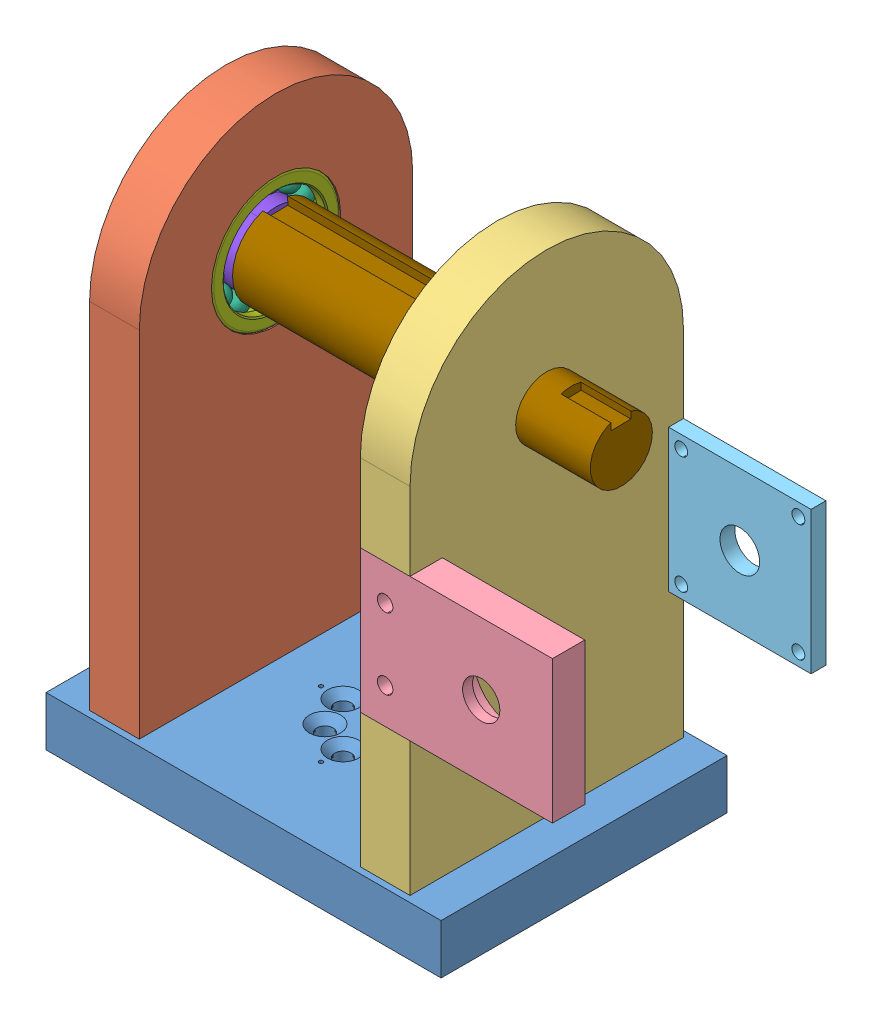
SolidWorks assembly Assem1, configuration Default. Lengths in mm.
Overall size (201.2 217.5 114.98).
38 component instances, 9 part files, 14 mates.
Components (placement in the parent):
- Baseplate rev2-1: Baseplate rev2 [Default] at (41.006 69.3734 140.8349) size (158.9 20 114.98)
- support plate-1: support plate [Default] at (-23.444 156.8734 140.8349) size (20 205 110)
- support plate 2-1: support plate 2 [Default] at (105.456 156.8734 140.8349) x (-1 0 0) z (0 0 -1) size (20 205 110)
- bracket2-1: bracket2 [Default] at (124.106 171.8734 195.8349) x (1 0 0) z (0 0 -1) size (77.3 57.3 13)
- bracket1-1: bracket1 [Default] at (124.106 171.8734 85.8349) size (77.3 57.3 6)
- 7205_BEP-1: 7205_BEP [Default] at (85.456 231.8734 140.8349) size (15 52 52)
  - 7205_BEP_3-1: 7205_BEP_3 [Default] x (1 0 0) z (0 -0.464723 0.885456) size (7.94 7.94 7.94)
  - 7205_BEP_3-2: 7205_BEP_3 [Default] x (1 0 0) z (0 -0.822984 0.568065) size (7.94 7.94 7.94)
  - 7205_BEP_3-3: 7205_BEP_3 [Default] x (1 0 0) z (0 -0.992709 0.120537) size (7.94 7.94 7.94)
  - 7205_BEP_3-4: 7205_BEP_3 [Default] x (1 0 0) z (0 -0.935016 -0.354605) size (7.94 7.94 7.94)
  - 7205_BEP_3-5: 7205_BEP_3 [Default] x (1 0 0) z (0 -0.663123 -0.748511) size (7.94 7.94 7.94)
  - 7205_BEP_3-6: 7205_BEP_3 [Default] x (1 0 0) z (0 -0.239316 -0.970942) size (7.94 7.94 7.94)
  - 7205_BEP_3-7: 7205_BEP_3 [Default] x (1 0 0) z (0 0.239316 -0.970942) size (7.94 7.94 7.94)
  - 7205_BEP_3-8: 7205_BEP_3 [Default] x (1 0 0) z (0 0.663123 -0.748511) size (7.94 7.94 7.94)
  - 7205_BEP_3-9: 7205_BEP_3 [Default] x (1 0 0) z (0 0.935016 -0.354605) size (7.94 7.94 7.94)
  - 7205_BEP_3-10: 7205_BEP_3 [Default] x (1 0 0) z (0 0.992709 0.120537) size (7.94 7.94 7.94)
  - 7205_BEP_3-11: 7205_BEP_3 [Default] x (1 0 0) z (0 0.822984 0.568065) size (7.94 7.94 7.94)
  - 7205_BEP_3-12: 7205_BEP_3 [Default] x (1 0 0) z (0 0.464723 0.885456) size (7.94 7.94 7.94)
  - 7205_BEP_3-13: 7205_BEP_3 [Default] at origin size (7.94 7.94 7.94)
  - 7205_BEP_17-1: 7205_BEP_17 [Default] at origin size (15 52 52)
  - 7205_BEP_19-1: 7205_BEP_19 [Default] at origin size (15 35.85 35.85)
- 7205_BEP-2: 7205_BEP [Default] at (-3.444 231.8734 140.8349) x (-1 0 0) z (0 -0.924225 -0.381849) size (15 52 52)
  - 7205_BEP_3-1: 7205_BEP_3 [Default] x (1 0 0) z (0 -0.464723 0.885456) size (7.94 7.94 7.94)
  - 7205_BEP_3-2: 7205_BEP_3 [Default] x (1 0 0) z (0 -0.822984 0.568065) size (7.94 7.94 7.94)
  - 7205_BEP_3-3: 7205_BEP_3 [Default] x (1 0 0) z (0 -0.992709 0.120537) size (7.94 7.94 7.94)
  - 7205_BEP_3-4: 7205_BEP_3 [Default] x (1 0 0) z (0 -0.935016 -0.354605) size (7.94 7.94 7.94)
  - 7205_BEP_3-5: 7205_BEP_3 [Default] x (1 0 0) z (0 -0.663123 -0.748511) size (7.94 7.94 7.94)
  - 7205_BEP_3-6: 7205_BEP_3 [Default] x (1 0 0) z (0 -0.239316 -0.970942) size (7.94 7.94 7.94)
  - 7205_BEP_3-7: 7205_BEP_3 [Default] x (1 0 0) z (0 0.239316 -0.970942) size (7.94 7.94 7.94)
  - 7205_BEP_3-8: 7205_BEP_3 [Default] x (1 0 0) z (0 0.663123 -0.748511) size (7.94 7.94 7.94)
  - 7205_BEP_3-9: 7205_BEP_3 [Default] x (1 0 0) z (0 0.935016 -0.354605) size (7.94 7.94 7.94)
  - 7205_BEP_3-10: 7205_BEP_3 [Default] x (1 0 0) z (0 0.992709 0.120537) size (7.94 7.94 7.94)
  - 7205_BEP_3-11: 7205_BEP_3 [Default] x (1 0 0) z (0 0.822984 0.568065) size (7.94 7.94 7.94)
  - 7205_BEP_3-12: 7205_BEP_3 [Default] x (1 0 0) z (0 0.464723 0.885456) size (7.94 7.94 7.94)
  - 7205_BEP_3-13: 7205_BEP_3 [Default] at origin size (7.94 7.94 7.94)
  - 7205_BEP_17-1: 7205_BEP_17 [Default] at origin size (15 52 52)
  - 7205_BEP_19-1: 7205_BEP_19 [Default] at origin size (15 35.85 35.85)
- Shoulder Keyed Output shaft rev2-2: Shoulder Keyed Output shaft rev2 [Default] at (135.456 231.8734 140.8349) x (-1 0 0) z (0 0.018335 -0.999832) size (153.9 34.27 35)
Mates (geometry in assembly coordinates):
- Coincident4: coincident anti-aligned: plane of Baseplate rev2-1 through (41.006 81.8734 140.8349) normal (0 1 0); plane of support plate-1 through (-3.444 81.8734 140.8349) normal (0 -1 0)
- Coincident5: coincident anti-aligned: plane of Baseplate rev2-1 through (-3.444 81.8734 85.8349) normal (-1 0 0); plane of support plate-1 through (-3.444 156.8734 140.8349) normal (1 0 0)
- Coincident6: coincident anti-aligned: plane of Baseplate rev2-1 through (-23.444 81.8734 195.8349) normal (0 0 -1); plane of support plate-1 through (-3.444 156.8734 195.8349) normal (0 0 1)
- Coincident16: coincident: point of Baseplate rev2-1; point of support plate 2-1
- Coincident17: coincident anti-aligned: plane of Baseplate rev2-1 through (85.456 81.8734 85.8349) normal (1 0 0); plane of support plate 2-1 through (85.456 156.8734 140.8349) normal (-1 0 0)
- Coincident19: coincident anti-aligned: circle of support plate 2-1; circle of bracket1-1
- Coincident27: coincident anti-aligned: circle of support plate 2-1; circle of bracket2-1
- Coincident28: coincident anti-aligned: plane of support plate 2-1 through (105.456 200.5234 195.8349) normal (0 -1 0); plane of bracket2-1 through (85.456 200.5234 182.8349) normal (0 1 0)
- Coincident29: coincident anti-aligned: plane of support plate 2-1 through (100.456 231.8734 140.8349) normal (-1 0 0); plane of 7205_BEP-1/7205_BEP_19-1 through (100.456 245.3734 140.8349) normal (1 0 0)
- Concentric1: concentric anti-aligned: cylinder of support plate 2-1 through (100.456 231.8734 140.8349) axis (-1 0 0) radius 26; cylinder of 7205_BEP-1/7205_BEP_17-1 through (100.456 231.8734 140.8349) axis (1 0 0) radius 26
- Coincident30: coincident anti-aligned: plane of support plate-1 through (-18.444 231.8734 140.8349) normal (1 0 0); plane of 7205_BEP-2/7205_BEP_19-1 through (-18.444 237.0284 128.3579) normal (-1 0 0)
- Concentric2: concentric anti-aligned: cylinder of support plate-1 through (-18.444 231.8734 140.8349) axis (1 0 0) radius 26; cylinder of 7205_BEP-2/7205_BEP_17-1 through (-18.444 231.8734 140.8349) axis (-1 0 0) radius 26
- Coincident33: coincident anti-aligned: plane of support plate-1 through (-18.444 231.8734 140.8349) normal (1 0 0); plane of Shoulder Keyed Output shaft rev2-2 through (-18.444 231.8734 140.8349) normal (-1 0 0)
- Concentric4: concentric anti-aligned: circle of support plate-1; circle of Shoulder Keyed Output shaft rev2-2
